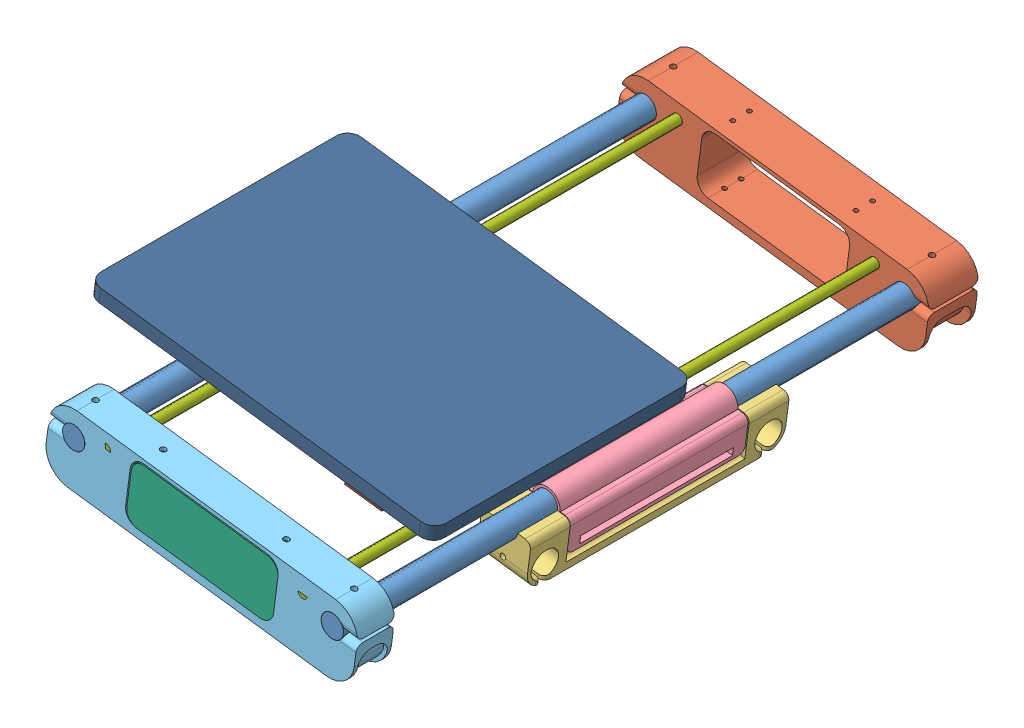
SolidWorks assembly Y_ASS, configuration Default. Lengths in mm.
Overall size (292.32 111.33 500).
14 component instances, 11 part files, 31 mates.
Components (placement in the parent):
- wood18x500-1: wood18x500 [Default] at (-231.4449 6.6322 -160.0216) x (0.923728 0.383049 0) z (0 0 -1) size (18 18 500)
- wood18x500-2: wood18x500 [Default] at (-23.2312 -20.6998 -160.0216) x (0.923728 0.383049 0) z (0 0 -1) size (18 18 500)
- Y_back-1: Y_back [Default] at (-132.0405 -12.2816 -620.0216) x (-0.991494 0.130152 0) z (0 0 -1) size (250 57.5 40)
- Y_framefix_1-1: Y_framefix_1 [Default] at (-46.1847 -41.8926 -451.7243) x (0 0 1) z (0.130152 0.991494 0) size (208 40 37.5)
- Y_framefix_2-1: Y_framefix_2 [Default] at (-23.2312 -20.6998 -475.2637) x (0.991494 -0.130152 0) z (-0.130152 -0.991494 0) size (40 143 37.25)
- Y_front_1-1: Y_front_1 [Default] at (-124.1493 -13.3175 -190.0216) x (0.991494 -0.130152 0) z (0 0 1) size (250 57.5 30)
- Y_front_2-1: Y_front_2 [Default] at (-127.8184 -14.5351 -190.0216) x (-0.991494 0.130152 0) z (0 0 1) size (119 47 30)
- Y_linearGuide-1: Y_linearGuide [Default] at (-205.6163 11.3103 -160.0216) x (0.923728 0.383049 0) z (0 0 -1) size (8 8 500)
- Y_linearGuide-2: Y_linearGuide [Default] at (-46.9773 -9.514 -160.0216) x (0.923728 0.383049 0) z (0 0 -1) size (8 8 500)
- Gt20-1: Gt20 [Valor predeterminado] at (-94.2037 -20.4605 -176.0216) x (0.130152 0.991494 0) z (0 0 1) size (18 8.6 18)
- bearing_esticador-1: bearing_esticador [Default] at (-126.2968 0.8981 -282.1082) x (0.991494 -0.130152 0) z (0 0 1) size (210 27 25)
- bearing_esticador-2: bearing_esticador [Default] at (-126.2968 0.8981 -417.1082) x (0.991494 -0.130152 0) z (0 0 1) size (210 27 25)
- hood-1: hood [Default] at (-152.8757 32.6273 -337.1082) x (0 0 1) z (-0.130152 -0.991494 0) size (210 280 11)
- correia-1: correia [Default] at (-82.6404 -19.9613 -259.1082) x (0 0 -1) z (0.130152 0.991494 0) size (21 30 4)
Mates (geometry in assembly coordinates):
- Concentric1: concentric aligned: cylinder of wood18x500-1 through (-231.4449 6.6322 -660.0216) axis (0 0 1) radius 9; cylinder of Y_back-1 through (-231.4449 6.6322 -660.0216) axis (0 0 1) radius 9.1
- Concentric2: concentric aligned: cylinder of wood18x500-2 through (-23.2312 -20.6998 -660.0216) axis (0 0 1) radius 9; cylinder of Y_back-1 through (-23.2312 -20.6998 -660.0216) axis (0 0 1) radius 9.1
- Concentric5: concentric aligned: cylinder of wood18x500-1 through (-231.4449 6.6322 -660.0216) axis (0 0 1) radius 9; circle of Y_front_1-1
- Concentric6: concentric anti-aligned: cylinder of wood18x500-2 through (-23.2312 -20.6998 -660.0216) axis (0 0 1) radius 9; cylinder of Y_front_1-1 through (-23.2312 -20.6998 -160.0216) axis (0 0 -1) radius 9.1
- Coincident4: coincident aligned: plane of wood18x500-2 through (-23.2312 -20.6998 -160.0216) normal (0 0 1); plane of Y_front_1-1 through (-25.5089 -38.0512 -160.0216) normal (0 0 1)
- Coincident5: coincident aligned: plane of wood18x500-2 through (-23.2312 -20.6998 -660.0216) normal (0 0 -1); plane of Y_back-1 through (-233.7226 -10.7193 -660.0216) normal (0 0 -1)
- Coincident6: coincident aligned: plane of wood18x500-1 through (-231.4449 6.6322 -660.0216) normal (0 0 -1); plane of wood18x500-2 through (-23.2312 -20.6998 -660.0216) normal (0 0 -1)
- Concentric7: concentric aligned: circle of Y_front_1-1; cylinder of Y_linearGuide-1 through (-205.6163 11.3103 -660.0216) axis (0 0 1) radius 4
- Coincident7: coincident aligned: plane of wood18x500-1 through (-231.4449 6.6322 -660.0216) normal (0 0 -1); plane of Y_linearGuide-1 through (-205.6163 11.3103 -660.0216) normal (0 0 -1)
- Coincident8: coincident aligned: plane of Y_front_1-1 through (-25.5089 -38.0512 -160.0216) normal (0 0 1); plane of Y_front_2-1 through (-80.0659 -34.9236 -160.0216) normal (0 0 1)
- Coincident9: coincident anti-aligned: plane of Y_front_1-1 through (-81.7981 -44.2777 -160.0216) normal (0.130152 0.991494 0); plane of Y_front_2-1 through (-130.877 -37.8352 -162.0216) normal (-0.130152 -0.991494 0)
- Coincident10: coincident anti-aligned: plane of Y_front_1-1 through (-70.5816 -35.6643 -160.0216) normal (-0.991494 0.130152 0); plane of Y_front_2-1 through (-68.8245 -22.2792 -162.0216) normal (0.991494 -0.130152 0)
- Concentric8: concentric anti-aligned: cylinder of wood18x500-2 through (-23.2312 -20.6998 -660.0216) axis (0 0 1) radius 9; cylinder of Y_framefix_1-1 through (-23.2312 -20.6998 -435.151) axis (0 0 -1) radius 9
- Coincident11: coincident aligned: plane of Y_framefix_1-1 through (-6.4599 -46.603 -494.2637) normal (0.991494 -0.130152 0); plane of Y_front_1-1 through (-3.4013 -23.3028 -160.0216) normal (0.991494 -0.130152 0)
- Concentric9: concentric anti-aligned: cylinder of wood18x500-2 through (-23.2312 -20.6998 -660.0216) axis (0 0 1) radius 9; cylinder of Y_framefix_2-1 through (-23.2312 -20.6998 -332.2637) axis (0 0 -1) radius 9.25
- Coincident13: coincident aligned: plane of Y_framefix_1-1 through (-46.1196 -41.3969 -494.2637) normal (-0.991494 0.130152 0); plane of Y_framefix_2-1 through (-46.445 -43.8756 -332.2637) normal (-0.991494 0.130152 0)
- Coincident14: coincident anti-aligned: plane of Y_framefix_1-1 through (-4.6377 -32.722 -332.2637) normal (0 0 -1); plane of Y_framefix_2-1 through (-23.2312 -20.6998 -332.2637) normal (0 0 1)
- Concentric10: concentric anti-aligned: cylinder of Y_front_1-1 through (-46.9773 -9.514 -160.0216) axis (0 0 -1) radius 4.125; cylinder of Y_linearGuide-2 through (-46.9773 -9.514 -660.0216) axis (0 0 1) radius 4
- Coincident15: coincident aligned: plane of wood18x500-2 through (-23.2312 -20.6998 -660.0216) normal (0 0 -1); plane of Y_linearGuide-2 through (-46.9773 -9.514 -660.0216) normal (0 0 -1)
- Coincident24: coincident anti-aligned: plane of Y_front_2-1 through (-102.7306 -19.3412 -176.0216) normal (0.991494 -0.130152 0); plane of Gt20-1 through (-103.9019 -28.2647 -176.0216) normal (-0.991494 0.130152 0)
- Concentric13: concentric aligned: cylinder of Y_front_2-1 through (-111.1583 -18.2349 -176.0216) axis (0.991494 -0.130152 0) radius 2.75; cylinder of Gt20-1 through (-94.2037 -20.4605 -176.0216) axis (0.991494 -0.130152 0) radius 2.5
- Concentric14: concentric anti-aligned: cylinder of Y_linearGuide-1 through (-205.6163 11.3103 -660.0216) axis (0 0 1) radius 4; cylinder of bearing_esticador-1 through (-205.6163 11.3103 -257.1082) axis (0 0 -1) radius 7.6
- Concentric15: concentric anti-aligned: cylinder of Y_linearGuide-2 through (-46.9773 -9.514 -660.0216) axis (0 0 1) radius 4; cylinder of bearing_esticador-1 through (-46.9773 -9.514 -257.1082) axis (0 0 -1) radius 7.6
- Concentric16: concentric anti-aligned: cylinder of Y_linearGuide-2 through (-46.9773 -9.514 -660.0216) axis (0 0 1) radius 4; cylinder of bearing_esticador-2 through (-46.9773 -9.514 -392.1082) axis (0 0 -1) radius 7.6
- Concentric17: concentric anti-aligned: cylinder of Y_linearGuide-1 through (-205.6163 11.3103 -660.0216) axis (0 0 1) radius 4; cylinder of bearing_esticador-2 through (-205.6163 11.3103 -392.1082) axis (0 0 -1) radius 7.6
- Coincident25: coincident anti-aligned: plane of bearing_esticador-2 through (-213.3187 29.4672 -392.1082) normal (0.130152 0.991494 0); plane of hood-1 through (-154.3074 21.7209 -337.1082) normal (-0.130152 -0.991494 0)
- Distance1: distance = 25 mm aligned: plane of bearing_esticador-1 through (-205.6163 11.3103 -257.1082) normal (0 0 1); plane of hood-1 through (-293.1165 39.9422 -232.1082) normal (0 0 1)
- Distance2: distance = 25 mm aligned: plane of bearing_esticador-2 through (-205.6163 11.3103 -417.1082) normal (0 0 -1); plane of hood-1 through (-293.1165 39.9422 -442.1082) normal (0 0 -1)
- Concentric18: concentric anti-aligned: cylinder of bearing_esticador-1 through (-84.0033 0.3892 -276.1082) axis (-0.130152 -0.991494 0) radius 1.95; circle of correia-1
- Concentric19: concentric aligned: cylinder of bearing_esticador-1 through (-105.8162 3.2526 -263.1082) axis (-0.130152 -0.991494 0) radius 1.95; cylinder of correia-1 through (-107.8986 -12.6113 -263.1082) axis (-0.130152 -0.991494 0) radius 1.75
- Distance3: distance = 1 mm: plane of bearing_esticador-1 through (-111.7344 -11.0992 -216.7473) normal (-0.130152 -0.991494 0); line of correia-1 through (-82.1198 -15.9953 -280.1082) axis (-0.991494 0.130152 0)
